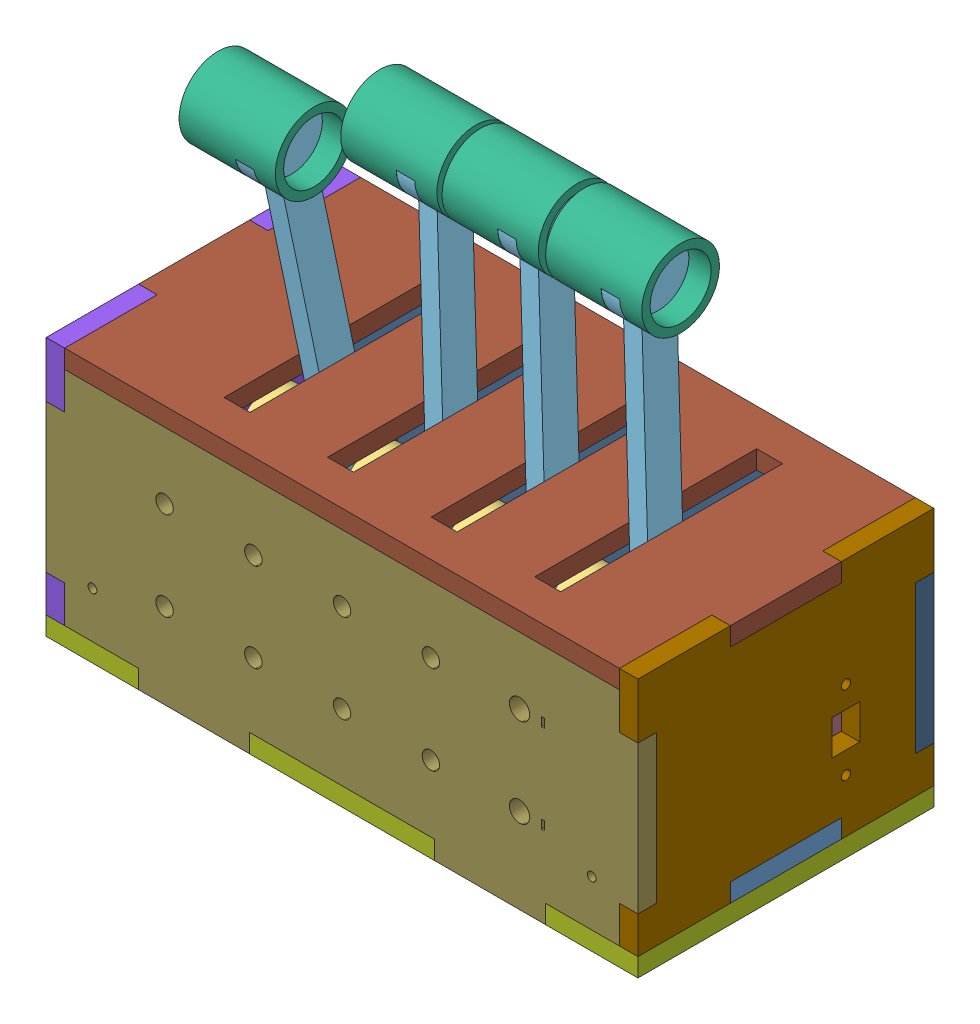
SolidWorks assembly baseKit1, configuration Default. Lengths in mm.
Overall size (203.2 178.77 101.6).
44 component instances, 15 part files, 69 mates.
Components (placement in the parent):
- basePlate1-1: basePlate1 [Default] at (-23.7637 -136.6857 -69.8214) size (203.2 6.35 88.9)
- mountBracket-1: mountBracket [Default] at (-87.5177 -136.6857 -69.8214) x (0 0 -1) z (1 0 0) size (30.48 57.15 6.35)
- mountBracket-2: mountBracket [Default] at (-51.9577 -136.6857 -69.8214) x (0 0 -1) z (1 0 0) size (30.48 57.15 6.35)
- mountBracket-3: mountBracket [Default] at (-17.1597 -136.6857 -69.8214) x (0 0 -1) z (1 0 0) size (30.48 57.15 6.35)
- mountBracket-4: mountBracket [Default] at (18.4003 -136.6857 -69.8214) x (0 0 -1) z (1 0 0) size (30.48 57.15 6.35)
- thrLever-1: thrLever [Default] at (-110.8992 -112.2426 -64.3738) x (0 0 -1) z (1 0 0) size (54.6 142.76 37.97) (flexible)
  - pot-1: pot [Default] at (3.3102 2.1897 -0.9568) size (23.98 26.99 33.53) (flexible)
    - potBody-1: potBody [Default] at (2.1373 17.8173 24.3383) size (23.98 26.99 20.83)
    - potShaft-1: potShaft [Default] at (2.1373 17.8173 24.3383) x (0.97897 0.204004 0) z (0 0 1) size (6.35 6.35 22.23)
  - lever-1: lever [Default] at (6.6716 14.1331 42.4315) x (0 0 -1) z (0.97897 0.204004 0) size (6.35 136.76 26.67)
  - leverTop-1: leverTop [Default] at (-17.87 131.9032 17.0315) x (0 0 1) z (-0.97897 -0.204004 0) size (33.02 26.67 26.67)
- thrLever-2: thrLever [Default] at (-75.3392 -112.2426 -64.3738) x (0 0 -1) z (1 0 0) size (30.78 143.06 37.97)
  - pot-1: pot [Default] at (3.3102 2.1897 -0.9568) size (23.98 26.99 33.53) (flexible)
    - potBody-1: potBody [Default] at (2.1373 17.8173 24.3383) size (23.98 26.99 20.83)
    - potShaft-1: potShaft [Default] at (2.1373 17.8173 24.3383) x (0.999564 0.029528 0) z (0 0 1) size (6.35 6.35 22.23)
  - lever-1: lever [Default] at (5.6248 14.0095 42.4315) x (0 0 -1) z (0.999564 0.029528 0) size (6.35 136.76 26.67)
  - leverTop-1: leverTop [Default] at (2.0726 134.2571 17.0315) x (0 0 1) z (-0.999564 -0.029528 0) size (33.02 26.67 26.67)
- thrLever-3: thrLever [Default] at (-40.5412 -112.2426 -64.3738) x (0 0 -1) z (1 0 0) size (30.78 143.06 37.97)
  - pot-1: pot [Default] at (3.3102 2.1897 -0.9568) size (23.98 26.99 33.53) (flexible)
    - potBody-1: potBody [Default] at (2.1373 17.8173 24.3383) size (23.98 26.99 20.83)
    - potShaft-1: potShaft [Default] at (2.1373 17.8173 24.3383) x (0.999564 0.029528 0) z (0 0 1) size (6.35 6.35 22.23)
  - lever-1: lever [Default] at (5.6248 14.0095 42.4315) x (0 0 -1) z (0.999564 0.029528 0) size (6.35 136.76 26.67)
  - leverTop-1: leverTop [Default] at (2.0726 134.2571 17.0315) x (0 0 1) z (-0.999564 -0.029528 0) size (33.02 26.67 26.67)
- thrLever-4: thrLever [Default] at (-4.9812 -112.2426 -64.3738) x (0 0 -1) z (1 0 0) size (30.78 143.06 37.97)
  - pot-1: pot [Default] at (3.3102 2.1897 -0.9568) size (23.98 26.99 33.53) (flexible)
    - potBody-1: potBody [Default] at (2.1373 17.8173 24.3383) size (23.98 26.99 20.83)
    - potShaft-1: potShaft [Default] at (2.1373 17.8173 24.3383) x (0.999564 0.029528 0) z (0 0 1) size (6.35 6.35 22.23)
  - lever-1: lever [Default] at (5.6248 14.0095 42.4315) x (0 0 -1) z (0.999564 0.029528 0) size (6.35 136.76 26.67)
  - leverTop-1: leverTop [Default] at (2.0726 134.2571 17.0315) x (0 0 1) z (-0.999564 -0.029528 0) size (33.02 26.67 26.67)
- basePlate2-1: basePlate2 [Default] at (-23.7637 -143.0357 -69.8214) size (203.2 6.35 101.6)
- sidePlate-1: sidePlate [Default] at (-125.3637 -95.4107 -69.8214) size (6.35 82.55 101.6)
- sidePlate-2-2: sidePlate-2 [Default] at (71.4863 -95.4107 -69.8214) size (6.35 82.55 101.6)
- backPlate-2: backPlate [Default] at (-23.7637 -98.5857 -120.6214) size (203.2 82.55 6.35)
- basePlate3-1: basePlate3 [Default] at (-23.7637 -60.4857 -69.8214) size (203.2 6.35 101.6)
- frontPlate-1: frontPlate [Default] at (-23.7637 -98.5857 -25.3714) size (203.2 82.55 6.35)
- usbPort-1: usbPort [Default] at (71.4863 -110.9365 -95.2214) x (0 1 0) z (1 0 0) size (38.1 9.53 28.58)
- lockTab-1: lockTab [Default] at (-109.4887 -125.8946 -30.9594) size (19.05 25.4 6.35)
- lockTab-2: lockTab [Default] at (61.9613 -125.8946 -30.9594) size (19.05 25.4 6.35)
- lockTab-3: lockTab [Default] at (61.9613 -125.8946 -114.2714) size (19.05 25.4 6.35)
- lockTab-4: lockTab [Default] at (-109.4887 -125.8946 -114.2714) size (19.05 25.4 6.35)
- dowelPin-1: dowelPin [Default] at (51.6743 -143.0357 -101.5714) size (7.11 13.46 6.35)
- dowelPin-2: dowelPin [Default] at (53.1983 -143.0357 -43.6594) size (7.11 13.46 6.35)
- dowelPin-3: dowelPin [Default] at (-107.8377 -143.0357 -43.6594) size (7.11 13.46 6.35)
- dowelPin-4: dowelPin [Default] at (-107.8377 -143.0357 -102.3334) size (7.11 13.46 6.35)
Mates (geometry in assembly coordinates):
- Coincident1: coincident anti-aligned: plane of basePlate1-1 through (-87.5177 -136.6857 -85.0614) normal (1 0 0); plane of mountBracket-1 through (-87.5177 -136.6857 -69.8214) normal (-1 0 0)
- Coincident2: coincident anti-aligned: plane of basePlate1-1 through (-87.5177 -136.6857 -54.5814) normal (0 0 -1); plane of mountBracket-1 through (-81.1677 -79.5357 -54.5814) normal (0 0 1)
- Coincident4: coincident anti-aligned: plane of basePlate1-1 through (-51.9577 -136.6857 -85.0614) normal (1 0 0); plane of mountBracket-2 through (-51.9577 -136.6857 -69.8214) normal (-1 0 0)
- Coincident5: coincident anti-aligned: plane of basePlate1-1 through (-51.9577 -136.6857 -85.0614) normal (0 0 1); plane of mountBracket-2 through (-45.6077 -79.5357 -85.0614) normal (0 0 -1)
- Coincident6: coincident aligned: plane of basePlate1-1 through (-23.7637 -136.6857 -69.8214) normal (0 -1 0); plane of mountBracket-1 through (-81.1677 -136.6857 -54.5814) normal (0 -1 0)
- Coincident7: coincident aligned: plane of basePlate1-1 through (-23.7637 -136.6857 -69.8214) normal (0 -1 0); plane of mountBracket-2 through (-45.6077 -136.6857 -54.5814) normal (0 -1 0)
- Coincident8: coincident anti-aligned: plane of basePlate1-1 through (-10.8097 -136.6857 -85.0614) normal (-1 0 0); plane of mountBracket-3 through (-10.8097 -136.6857 -69.8214) normal (1 0 0)
- Coincident9: coincident anti-aligned: plane of basePlate1-1 through (-16.3977 -136.6857 -54.5814) normal (0 0 -1); plane of mountBracket-3 through (-10.8097 -79.5357 -54.5814) normal (0 0 1)
- Coincident10: coincident aligned: plane of basePlate1-1 through (-23.7637 -136.6857 -69.8214) normal (0 -1 0); plane of mountBracket-3 through (-10.8097 -136.6857 -54.5814) normal (0 -1 0)
- Coincident11: coincident anti-aligned: plane of basePlate1-1 through (24.7503 -136.6857 -85.0614) normal (-1 0 0); plane of mountBracket-4 through (24.7503 -136.6857 -69.8214) normal (1 0 0)
- Coincident12: coincident anti-aligned: plane of basePlate1-1 through (19.1623 -136.6857 -85.0614) normal (0 0 1); plane of mountBracket-4 through (24.7503 -79.5357 -85.0614) normal (0 0 -1)
- Coincident13: coincident aligned: plane of basePlate1-1 through (-23.7637 -136.6857 -69.8214) normal (0 -1 0); plane of mountBracket-4 through (24.7503 -136.6857 -54.5814) normal (0 -1 0)
- Concentric3: concentric aligned: cylinder of mountBracket-1 through (-81.1677 -92.2357 -69.8214) axis (-1 0 0) radius 4.7625; cylinder of thrLever-1/pot-1/potBody-1 through (-77.9927 -92.2357 -69.8214) axis (-1 0 0) radius 4.7625
- Coincident18: coincident anti-aligned: plane of mountBracket-1 through (-81.1677 -90.9467 -57.8326) normal (0 0 -1); plane of thrLever-1/pot-1/potBody-1 through (-83.4537 -94.3185 -57.8326) normal (0 0 1)
- Coincident19: coincident anti-aligned: plane of mountBracket-1 through (-87.5177 -136.6857 -69.8214) normal (-1 0 0); plane of thrLever-1/pot-1/potBody-1 through (-87.5177 -92.2357 -69.8214) normal (1 0 0)
- Concentric4: concentric aligned: cylinder of mountBracket-2 through (-45.6077 -92.2357 -69.8214) axis (-1 0 0) radius 4.7625; cylinder of thrLever-2/pot-1/potBody-1 through (-42.4327 -92.2357 -69.8214) axis (-1 0 0) radius 4.7625
- Coincident20: coincident anti-aligned: plane of mountBracket-2 through (-45.6077 -90.9467 -57.8326) normal (0 0 -1); plane of thrLever-2/pot-1/potBody-1 through (-47.8937 -94.3185 -57.8326) normal (0 0 1)
- Coincident21: coincident anti-aligned: plane of mountBracket-2 through (-51.9577 -136.6857 -69.8214) normal (-1 0 0); plane of thrLever-2/pot-1/potBody-1 through (-51.9577 -92.2357 -69.8214) normal (1 0 0)
- Concentric5: concentric aligned: cylinder of mountBracket-3 through (-10.8097 -92.2357 -69.8214) axis (-1 0 0) radius 4.7625; cylinder of thrLever-3/pot-1/potBody-1 through (-7.6347 -92.2357 -69.8214) axis (-1 0 0) radius 4.7625
- Parallel2: parallel anti-aligned: plane of mountBracket-3 through (-10.8097 -90.9467 -57.8326) normal (0 0 -1); plane of thrLever-3/pot-1/potBody-1 through (-13.0957 -94.3185 -57.8326) normal (0 0 1)
- Coincident23: coincident anti-aligned: plane of mountBracket-3 through (-17.1597 -136.6857 -69.8214) normal (-1 0 0); plane of thrLever-3/pot-1/potBody-1 through (-17.1597 -92.2357 -69.8214) normal (1 0 0)
- Concentric6: concentric aligned: cylinder of mountBracket-4 through (24.7503 -92.2357 -69.8214) axis (-1 0 0) radius 4.7625; cylinder of thrLever-4/pot-1/potBody-1 through (27.9253 -92.2357 -69.8214) axis (-1 0 0) radius 4.7625
- Coincident24: coincident anti-aligned: plane of mountBracket-4 through (24.7503 -90.9467 -57.8326) normal (0 0 -1); plane of thrLever-4/pot-1/potBody-1 through (22.4643 -94.3185 -57.8326) normal (0 0 1)
- Coincident25: coincident anti-aligned: plane of mountBracket-4 through (18.4003 -136.6857 -69.8214) normal (-1 0 0); plane of thrLever-4/pot-1/potBody-1 through (18.4003 -92.2357 -69.8214) normal (1 0 0)
- Distance1: distance = 6.35 mm aligned: plane of basePlate1-1 through (-119.0137 -130.3357 -114.2714) normal (0 0 -1); plane of basePlate2-1 through (-23.7637 -136.6857 -120.6214) normal (0 0 -1)
- Distance2: distance = 6.35 mm aligned: plane of basePlate1-1 through (-119.0137 -130.3357 -25.3714) normal (-1 0 0); plane of basePlate2-1 through (-125.3637 -136.6857 -69.8214) normal (-1 0 0)
- Coincident29: coincident aligned: plane of basePlate2-1 through (-23.7637 -136.6857 -19.0214) normal (0 0 1); plane of sidePlate-1 through (-119.0137 -95.4107 -19.0214) normal (0 0 1)
- Coincident32: coincident aligned: plane of basePlate2-1 through (-23.7637 -136.6857 -120.6214) normal (0 0 -1); plane of sidePlate-2-2 through (77.8363 -95.4107 -120.6214) normal (0 0 -1)
- Coincident38: coincident anti-aligned: plane of basePlate1-1 through (71.4863 -130.3357 -25.3714) normal (1 0 0); plane of sidePlate-2-2 through (71.4863 -95.4107 -69.8214) normal (-1 0 0)
- Coincident39: coincident anti-aligned: plane of basePlate1-1 through (-119.0137 -130.3357 -25.3714) normal (-1 0 0); plane of sidePlate-1 through (-119.0137 -95.4107 -69.8214) normal (1 0 0)
- Coincident41: coincident anti-aligned: plane of basePlate1-1 through (-23.7637 -136.6857 -69.8214) normal (0 -1 0); plane of basePlate2-1 through (-23.7637 -136.6857 -69.8214) normal (0 1 0)
- Coincident45: coincident anti-aligned: plane of basePlate1-1 through (-23.7637 -130.3357 -69.8214) normal (0 1 0); plane of sidePlate-2-2 through (77.8363 -130.3357 -69.8214) normal (0 -1 0)
- Coincident46: coincident anti-aligned: plane of sidePlate-1 through (-119.0137 -73.1857 -69.8214) normal (0 -1 0); plane of backPlate-2 through (-125.3637 -73.1857 -120.6214) normal (0 1 0)
- Coincident47: coincident aligned: plane of sidePlate-1 through (-125.3637 -95.4107 -69.8214) normal (-1 0 0); plane of backPlate-2 through (-125.3637 -98.5857 -120.6214) normal (-1 0 0)
- Coincident48: coincident aligned: plane of basePlate2-1 through (-23.7637 -136.6857 -120.6214) normal (0 0 -1); plane of backPlate-2 through (-23.7637 -98.5857 -120.6214) normal (0 0 -1)
- Coincident50: coincident aligned: plane of sidePlate-1 through (-125.3637 -95.4107 -69.8214) normal (-1 0 0); plane of basePlate3-1 through (-125.3637 -60.4857 -69.8214) normal (-1 0 0)
- Coincident51: coincident aligned: plane of backPlate-2 through (-23.7637 -98.5857 -120.6214) normal (0 0 -1); plane of basePlate3-1 through (-119.0137 -54.1357 -120.6214) normal (0 0 -1)
- Coincident52: coincident aligned: plane of sidePlate-2-2 through (77.8363 -54.1357 -69.8214) normal (0 1 0); plane of basePlate3-1 through (-23.7637 -54.1357 -69.8214) normal (0 1 0)
- Coincident53: coincident aligned: plane of sidePlate-2-2 through (77.8363 -95.4107 -69.8214) normal (1 0 0); plane of frontPlate-1 through (77.8363 -98.5857 -25.3714) normal (1 0 0)
- Coincident54: coincident aligned: plane of basePlate2-1 through (-23.7637 -143.0357 -69.8214) normal (0 -1 0); plane of frontPlate-1 through (-23.7637 -143.0357 -25.3714) normal (0 -1 0)
- Coincident55: coincident anti-aligned: plane of basePlate2-1 through (-23.7637 -136.6857 -25.3714) normal (0 0 1); plane of frontPlate-1 through (-23.7637 -98.5857 -25.3714) normal (0 0 -1)
- Coincident56: coincident anti-aligned: plane of basePlate2-1 through (-23.7637 -136.6857 -69.8214) normal (0 1 0); plane of sidePlate-1 through (-119.0137 -136.6857 -69.8214) normal (0 -1 0)
- Coincident58: coincident anti-aligned: plane of sidePlate-2-2 through (71.4863 -95.4107 -69.8214) normal (-1 0 0); plane of usbPort-1 through (71.4863 -98.935 -95.2214) normal (1 0 0)
- Coincident61: coincident anti-aligned: plane of basePlate1-1 through (-119.0137 -136.6858 -30.9594) normal (0 0 1); plane of lockTab-1 through (-109.4887 -125.8946 -30.9594) normal (0 0 -1)
- Coincident62: coincident anti-aligned: plane of basePlate1-1 through (-99.9637 -136.6858 -25.3714) normal (-1 0 0); plane of lockTab-1 through (-99.9637 -136.6857 -24.6094) normal (1 0 0)
- Coincident63: coincident anti-aligned: plane of basePlate2-1 through (-23.7637 -136.6857 -69.8214) normal (0 1 0); plane of lockTab-1 through (-119.0137 -136.6857 -24.6094) normal (0 -1 0)
- Distance3: distance = 19.05 mm anti-aligned: plane of backPlate-2 through (-23.7637 -98.5857 -114.2714) normal (0 0 1); plane of usbPort-1 through (65.1363 -110.9365 -95.2214) normal (0 0 -1)
- Distance4: distance = 6.35 mm anti-aligned: plane of basePlate1-1 through (-23.7637 -130.3357 -69.8214) normal (0 1 0); plane of usbPort-1 through (42.9113 -123.9857 -85.6964) normal (0 -1 0)
- Coincident64: coincident anti-aligned: plane of basePlate1-1 through (71.4863 -136.6858 -30.9594) normal (0 0 1); plane of lockTab-2 through (61.9613 -125.8946 -30.9594) normal (0 0 -1)
- Coincident65: coincident anti-aligned: plane of basePlate1-1 through (52.4363 -136.6858 -25.3714) normal (1 0 0); plane of lockTab-2 through (52.4363 -136.6857 -24.6094) normal (-1 0 0)
- Coincident66: coincident anti-aligned: plane of basePlate2-1 through (-23.7637 -136.6857 -69.8214) normal (0 1 0); plane of lockTab-2 through (52.4363 -136.6857 -24.6094) normal (0 -1 0)
- Coincident67: coincident anti-aligned: plane of basePlate1-1 through (71.4863 -136.6858 -107.9214) normal (0 0 -1); plane of lockTab-3 through (61.9613 -125.8946 -107.9214) normal (0 0 1)
- Coincident68: coincident anti-aligned: plane of basePlate1-1 through (52.4363 -136.6858 -114.2714) normal (1 0 0); plane of lockTab-3 through (52.4363 -136.6857 -107.9214) normal (-1 0 0)
- Coincident69: coincident anti-aligned: plane of basePlate2-1 through (-23.7637 -136.6857 -69.8214) normal (0 1 0); plane of lockTab-3 through (52.4363 -136.6857 -107.9214) normal (0 -1 0)
- Coincident70: coincident anti-aligned: plane of basePlate1-1 through (-119.0137 -136.6858 -107.9214) normal (0 0 -1); plane of lockTab-4 through (-109.4887 -125.8946 -107.9214) normal (0 0 1)
- Coincident71: coincident anti-aligned: plane of basePlate2-1 through (-23.7637 -136.6857 -69.8214) normal (0 1 0); plane of lockTab-4 through (-119.0137 -136.6857 -107.9214) normal (0 -1 0)
- Coincident72: coincident anti-aligned: plane of basePlate1-1 through (-99.9637 -136.6858 -114.2714) normal (-1 0 0); plane of lockTab-4 through (-99.9637 -136.6857 -107.9214) normal (1 0 0)
- Coincident73: coincident anti-aligned: plane of basePlate2-1 through (-23.7637 -136.6857 -101.5714) normal (0 0 1); plane of dowelPin-1 through (51.6743 -143.0357 -101.5714) normal (0 0 -1)
- Coincident74: coincident anti-aligned: plane of basePlate2-1 through (58.7863 -136.6857 -69.8214) normal (-1 0 0); plane of dowelPin-1 through (58.7863 -143.0357 -95.2214) normal (1 0 0)
- Coincident75: coincident aligned: plane of basePlate2-1 through (-23.7637 -143.0357 -69.8214) normal (0 -1 0); plane of dowelPin-1 through (51.6743 -143.0357 -95.2214) normal (0 -1 0)
- Coincident79: coincident anti-aligned: plane of basePlate2-1 through (-23.7637 -136.6857 -43.6594) normal (0 0 1); plane of dowelPin-2 through (53.1983 -143.0357 -43.6594) normal (0 0 -1)
- Coincident80: coincident anti-aligned: plane of basePlate2-1 through (53.1983 -136.6857 -69.8214) normal (1 0 0); plane of dowelPin-2 through (53.1983 -143.0357 -37.3094) normal (-1 0 0)
- Coincident81: coincident aligned: plane of basePlate2-1 through (-23.7637 -143.0357 -69.8214) normal (0 -1 0); plane of dowelPin-2 through (53.1983 -143.0357 -37.3094) normal (0 -1 0)
- Coincident82: coincident anti-aligned: plane of basePlate2-1 through (-100.7257 -136.6857 -69.8214) normal (-1 0 0); plane of dowelPin-3 through (-100.7257 -143.0357 -37.3094) normal (1 0 0)
- Coincident83: coincident anti-aligned: plane of basePlate2-1 through (-23.7637 -136.6857 -43.6594) normal (0 0 1); plane of dowelPin-3 through (-107.8377 -143.0357 -43.6594) normal (0 0 -1)
- Coincident84: coincident aligned: plane of basePlate2-1 through (-23.7637 -143.0357 -69.8214) normal (0 -1 0); plane of dowelPin-3 through (-107.8377 -143.0357 -37.3094) normal (0 -1 0)
- Coincident85: coincident anti-aligned: plane of basePlate2-1 through (-23.7637 -136.6857 -95.9834) normal (0 0 -1); plane of dowelPin-4 through (-107.8377 -143.0357 -95.9834) normal (0 0 1)
- Coincident86: coincident anti-aligned: plane of basePlate2-1 through (-100.7257 -136.6857 -69.8214) normal (-1 0 0); plane of dowelPin-4 through (-100.7257 -143.0357 -95.9834) normal (1 0 0)
- Coincident87: coincident aligned: plane of basePlate2-1 through (-23.7637 -143.0357 -69.8214) normal (0 -1 0); plane of dowelPin-4 through (-107.8377 -143.0357 -95.9834) normal (0 -1 0)
